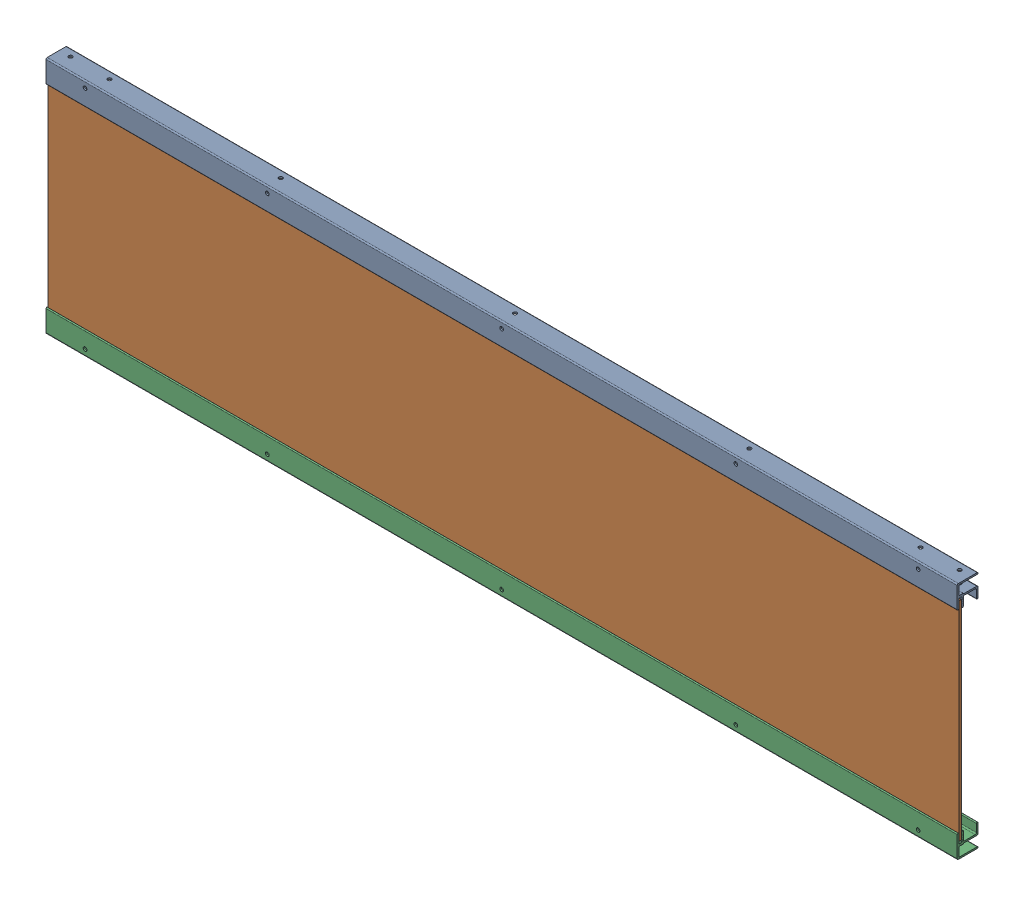
SolidWorks assembly FIELD_RelicRecovery_Rail Final Asm, configuration Default. Lengths in mm.
Overall size (1185.42 310.9 27.05).
3 component instances, 2 part files, 0 mates.
Components (placement in the parent):
- FIELD_RelicRecovery_NewRail-1: FIELD_RelicRecovery_NewRail [Default] at (-479.9559 232.0754 95.5976) size (1185.42 29.72 27.05)
- FIELD_RelicRecovery_New FTC Side Glass-1: FIELD_RelicRecovery_New FTC Side Glass [Default] at (112.7531 85.1364 102.7604) size (1185.42 270.76 3)
- FIELD_RelicRecovery_NewRail-2: FIELD_RelicRecovery_NewRail [Default] at (705.4621 -61.8026 95.5976) x (-1 0 0) z (0 0 1) size (1185.42 29.72 27.05)
